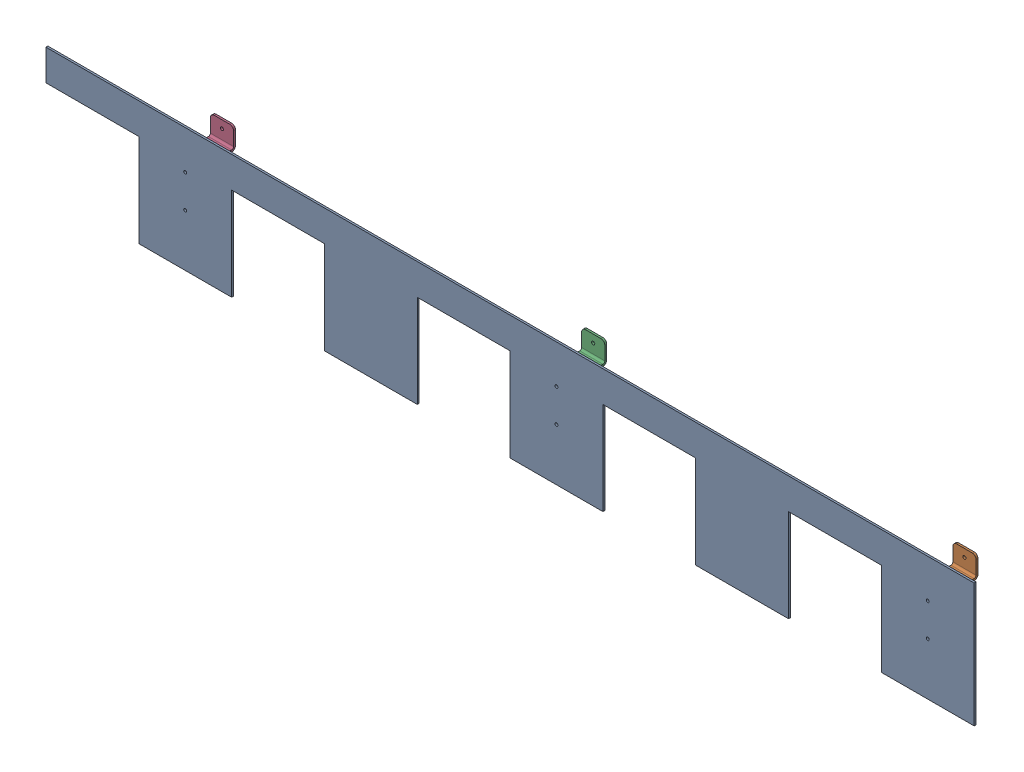
SolidWorks assembly GE-16133_ASM, configuration Default. Lengths in mm.
Overall size (1524 203.2 63.5).
4 component instances, 2 part files, 0 mates.
Components (placement in the parent):
- GE-16134-1: GE-16134 [Default] at origin size (1524 203.2 3.17)
- GE-16135-1: GE-16135 [Default] at (685.8 50.8 0) x (-1 0 0) z (0 1 0) size (38.1 60.32 107.95)
- GE-16135-2: GE-16135 [Default] at (76.2 50.8 0) x (-1 0 0) z (0 1 0) size (38.1 60.32 107.95)
- GE-16135-3: GE-16135 [Default] at (-533.4 50.8 0) x (-1 0 0) z (0 1 0) size (38.1 60.32 107.95)
